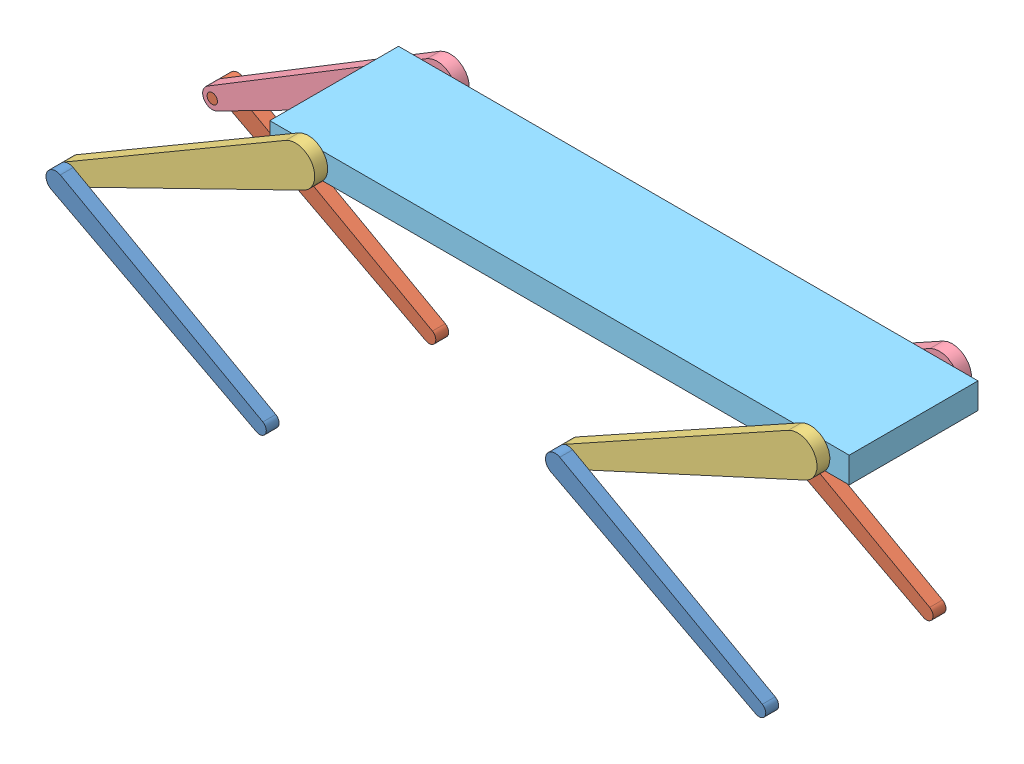
SolidWorks assembly Assem4, configuration Default. Lengths in mm.
Overall size (610 208.51 140).
10 component instances, 6 part files, 16 mates.
Components (placement in the parent):
- leg1-1: leg1 [Default] at (-282.2499 85.3321 373.3235) size (171.13 98.14 20)
- leg2-1: leg2 [Default] at (-282.309 85.4491 273.3235) size (171.13 98.14 20)
- thigh1-1: thigh1 [Default] at (-303.8119 175.6642 363.3235) x (0.89219 0.45166 0) z (0 0 1) size (222.5 30 20)
- thigh2-1: thigh2 [Default] at (-303.8119 175.6642 283.3235) x (0.892486 0.451075 0) z (0 0 1) size (222.5 30 20)
- Part7-1: Part7 [Default] at origin
- base1-1: base1 [Default] at (-498.8119 165.6642 313.3235) size (450 20 100)
- thigh2-2: thigh2 [Default] at (-693.8119 175.6642 283.3235) x (0.873234 0.4873 0) z (0 0 1) size (222.5 30 20)
- leg2-2: leg2 [Default] at (-668.4587 78.2041 273.3235) size (171.13 98.14 20)
- thigh1-2: thigh1 [Default] at (-693.8119 175.6642 363.3235) x (0.881551 0.472089 0) z (0 0 1) size (222.5 30 20)
- leg1-2: leg1 [Default] at (-670.122 81.2463 373.3235) size (171.13 98.14 20)
Mates (geometry in assembly coordinates):
- Concentric1: concentric aligned: cylinder of thigh1-1 through (-303.8119 175.6642 353.3235) axis (0 0 1) radius 8; cylinder of base1-1 through (-303.8119 175.6642 263.3235) axis (0 0 1) radius 8
- Coincident1: coincident anti-aligned: plane of thigh1-1 through (-303.8119 175.6642 363.3235) normal (0 0 -1); plane of base1-1 through (-723.8119 185.6642 363.3235) normal (0 0 1)
- Concentric2: concentric anti-aligned: cylinder of thigh2-1 through (-303.8119 175.6642 273.3235) axis (0 0 -1) radius 8; cylinder of base1-1 through (-303.8119 175.6642 263.3235) axis (0 0 1) radius 8
- Coincident2: coincident anti-aligned: plane of thigh2-1 through (-303.8119 175.6642 263.3235) normal (0 0 1); plane of base1-1 through (-723.8119 185.6642 263.3235) normal (0 0 -1)
- Concentric3: concentric anti-aligned: cylinder of leg1-1 through (-482.2499 85.3321 363.3235) axis (0 0 1) radius 4; cylinder of thigh1-1 through (-482.2499 85.3321 423.3235) axis (0 0 -1) radius 4
- Coincident3: coincident anti-aligned: plane of leg1-1 through (-282.2499 85.3321 373.3235) normal (0 0 -1); plane of thigh1-1 through (-303.8119 175.6642 373.3235) normal (0 0 1)
- Concentric4: concentric anti-aligned: cylinder of leg2-1 through (-482.309 85.4491 263.3235) axis (0 0 -1) radius 4; cylinder of thigh2-1 through (-482.309 85.4491 203.3235) axis (0 0 1) radius 4
- Coincident4: coincident anti-aligned: plane of leg2-1 through (-282.309 85.4491 253.3235) normal (0 0 1); plane of thigh2-1 through (-303.8119 175.6642 253.3235) normal (0 0 -1)
- Concentric5: concentric anti-aligned: cylinder of base1-1 through (-693.8119 175.6642 263.3235) axis (0 0 1) radius 8; cylinder of thigh2-2 through (-693.8119 175.6642 273.3235) axis (0 0 -1) radius 8
- Coincident5: coincident anti-aligned: plane of base1-1 through (-723.8119 185.6642 263.3235) normal (0 0 -1); plane of thigh2-2 through (-693.8119 175.6642 263.3235) normal (0 0 1)
- Concentric6: concentric anti-aligned: cylinder of thigh2-2 through (-868.4587 78.2041 203.3235) axis (0 0 1) radius 4; cylinder of leg2-2 through (-868.4587 78.2041 263.3235) axis (0 0 -1) radius 4
- Coincident6: coincident anti-aligned: plane of thigh2-2 through (-693.8119 175.6642 253.3235) normal (0 0 -1); plane of leg2-2 through (-668.4587 78.2041 253.3235) normal (0 0 1)
- Concentric7: concentric aligned: cylinder of base1-1 through (-693.8119 175.6642 263.3235) axis (0 0 1) radius 8; cylinder of thigh1-2 through (-693.8119 175.6642 353.3235) axis (0 0 1) radius 8
- Coincident8: coincident anti-aligned: plane of base1-1 through (-723.8119 185.6642 363.3235) normal (0 0 1); plane of thigh1-2 through (-693.8119 175.6642 363.3235) normal (0 0 -1)
- Concentric8: concentric anti-aligned: cylinder of thigh1-2 through (-870.122 81.2463 423.3235) axis (0 0 -1) radius 4; cylinder of leg1-2 through (-870.122 81.2463 363.3235) axis (0 0 1) radius 4
- Coincident9: coincident anti-aligned: plane of thigh1-2 through (-693.8119 175.6642 373.3235) normal (0 0 1); plane of leg1-2 through (-670.122 81.2463 373.3235) normal (0 0 -1)
